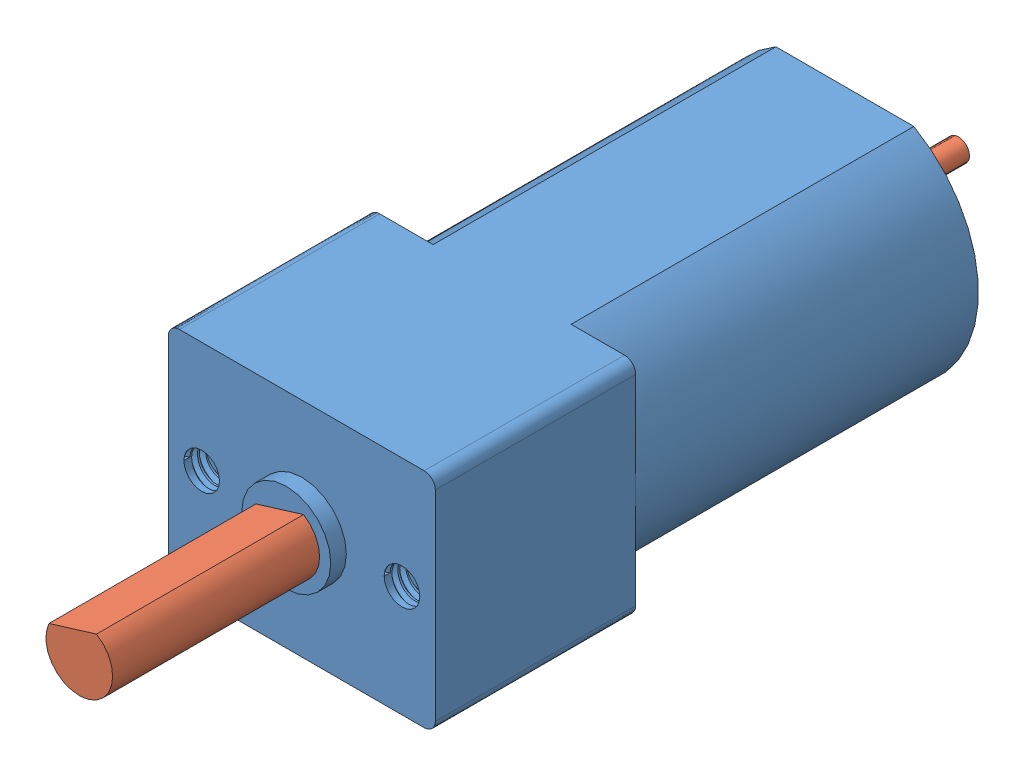
SolidWorks assembly Assem1, configuration Default. Lengths in mm.
Overall size (12 10 39.5).
2 component instances, 2 part files, 2 mates.
Components (placement in the parent):
- Motor_Gearbox-1: Motor_Gearbox [Default] at (14.9911 24.4599 -12.2783) size (12 10 25.9)
- Motor_Gearbox_Driveshaft-1: Motor_Gearbox_Driveshaft [Default] at (14.9911 24.4599 -41.7783) x (0.956114 0.292994 0) z (0 0 1) size (3 2.5 39.5)
Mates (geometry in assembly coordinates):
- Coincident1: coincident: plane of Motor_Gearbox-1 through (14.9911 24.4599 -11.5783) normal (0 0 1); plane of Motor_Gearbox_Driveshaft-1 through (14.9911 24.4599 -11.5783) normal (0 0 -1)
- Concentric1: concentric: circle of Motor_Gearbox-1; circle of Motor_Gearbox_Driveshaft-1
